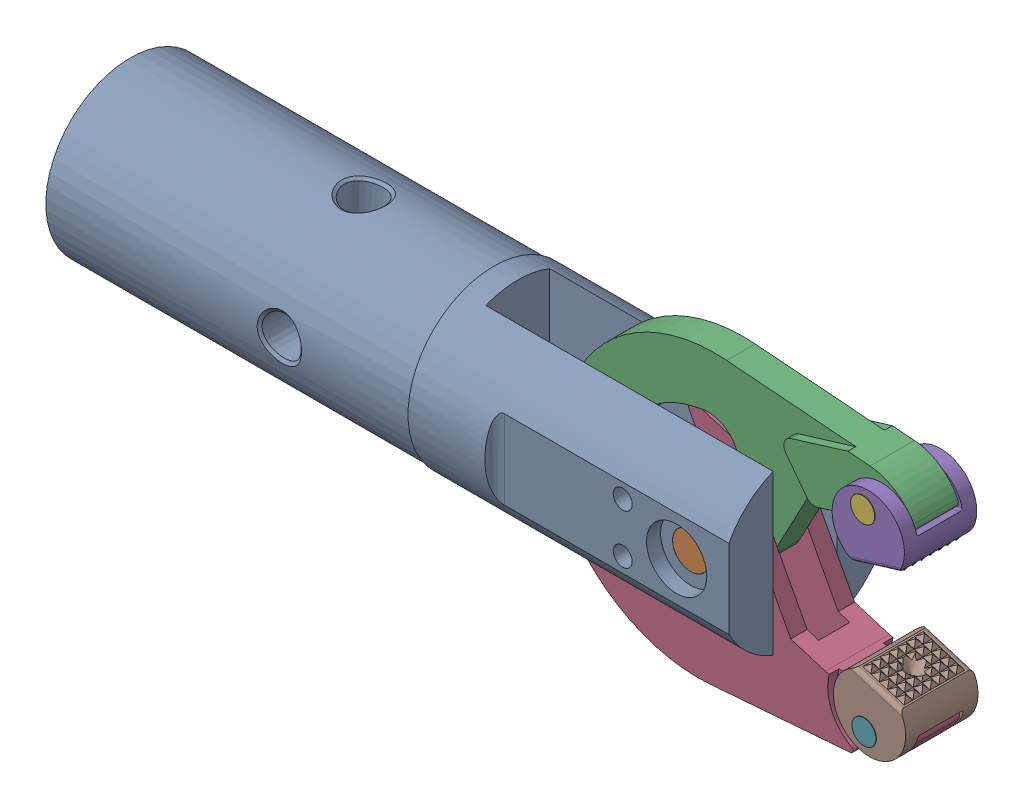
SolidWorks assembly Assem3, configuration Default. Lengths in mm.
Overall size (217.52 103.89 45.21).
8 component instances, 6 part files, 18 mates.
Components (placement in the parent):
- Body-1: Body [Default] at origin size (177.75 45.21 45.21)
- Large_Pin-1: Large_Pin [Default] at (-13.7795 0 -0.1524) x (-0.791073 -0.611722 0) z (0 0 1) size (9.53 9.53 32.77)
- Arm1-1: Arm1 [Default] at (-13.7795 0 0.3302) x (-0.956305 -0.292372 0) z (0 0 -1) size (103 45.53 11.68)
- Arm2-1: Arm2 [Default] at (-13.7795 0 0) x (-0.956305 0.292372 0) z (0 0 1) size (103 45.53 16.81)
- Grip-1: Grip [Default] at (26.2999 20.9388 0.1524) x (0 0 -1) z (0.956305 0.292372 0) size (19.05 17.93 19.05)
- Small_Pin-1: Small_Pin [Default] at (24.926 25.4325 0.4064) x (-0.970898 -0.239493 0) z (0 0 1) size (6.35 6.35 19.16)
- Small_Pin-2: Small_Pin [Default] at (24.926 -25.4325 0.0762) size (6.35 6.35 19.16)
- Grip-2: Grip [Default] at (26.2999 -20.9388 -0.1778) x (0 0 -1) z (-0.956305 0.292372 0) size (19.05 17.93 19.05)
Mates (geometry in assembly coordinates):
- Concentric1: concentric anti-aligned: cylinder of Body-1 through (-13.7795 0 -22.606) axis (0 0 1) radius 4.7892; cylinder of Large_Pin-1 through (-13.7795 0 18.6436) axis (0 0 -1) radius 4.7625
- Concentric2: concentric aligned: cylinder of Large_Pin-1 through (-13.7795 0 18.6436) axis (0 0 -1) radius 4.7625; cylinder of Arm1-1 through (-13.7795 0 6.1722) axis (0 0 -1) radius 4.7688
- Concentric3: concentric anti-aligned: cylinder of Large_Pin-1 through (-13.7795 0 18.6436) axis (0 0 -1) radius 4.7625; cylinder of Arm2-1 through (-13.7795 0 -8.4074) axis (0 0 1) radius 4.7688
- Coincident1: coincident aligned: plane of Body-1 through (-13.7795 0 16.3576) normal (0 0 1); plane of Large_Pin-1 through (-13.7795 0 16.3576) normal (0 0 1)
- Concentric4: concentric anti-aligned: cylinder of Arm1-1 through (18.5039 33.207 6.1722) axis (0 0 -1) radius 3.1813; cylinder of Small_Pin-1 through (18.5039 33.207 -12.0586) axis (0 0 1) radius 3.175
- Concentric5: concentric anti-aligned: cylinder of Grip-1 through (18.5039 33.207 9.6774) axis (0 0 -1) radius 3.1877; cylinder of Small_Pin-1 through (18.5039 33.207 -12.0586) axis (0 0 1) radius 3.175
- Concentric6: concentric aligned: cylinder of Arm2-1 through (29.5131 -16.4522 -8.4074) axis (0 0 1) radius 3.1813; cylinder of Small_Pin-2 through (29.5131 -16.4522 -12.3888) axis (0 0 1) radius 3.175
- Concentric7: concentric anti-aligned: cylinder of Small_Pin-2 through (29.5131 -16.4522 -12.3888) axis (0 0 1) radius 3.175; cylinder of Grip-2 through (29.5131 -16.4522 9.3472) axis (0 0 -1) radius 3.1877
- Coincident2: coincident aligned: plane of Grip-1 through (20.8178 29.1172 -9.3726) normal (0 0 -1); plane of Small_Pin-1 through (18.5039 33.207 -9.3726) normal (0 0 -1)
- Coincident3: coincident aligned: plane of Small_Pin-2 through (29.5131 -16.4522 -9.7028) normal (0 0 -1); plane of Grip-2 through (29.8818 -11.7677 -9.7028) normal (0 0 -1)
- Coincident4: coincident anti-aligned: plane of Arm1-1 through (11.7571 18.8254 6.1722) normal (0 0 1); plane of Grip-1 through (52.0249 57.7171 6.1722) normal (0 0 -1)
- Coincident5: coincident anti-aligned: plane of Arm2-1 through (17.3205 -6.2694 5.842) normal (0 0 1); plane of Grip-2 through (-11.9828 -18.0273 5.842) normal (0 0 -1)
- Coincident6: coincident anti-aligned: plane of Arm1-1 through (15.9696 66.4432 4.0894) normal (0 0 1); plane of Arm2-1 through (41.2625 -47.6454 4.0894) normal (0 0 -1)
- Coincident7: coincident anti-aligned: plane of Body-1 through (-75.692 -22.606 8.4074) normal (0 0 -1); plane of Arm2-1 through (41.2625 -47.6454 8.4074) normal (0 0 1)
- Parallel1: parallel anti-aligned: plane of Arm1-1 through (12.192 23.8868 4.0894) normal (0.492424 -0.870356 0); plane of Grip-1 through (57.153 48.6532 6.1722) normal (-0.492424 0.870356 0)
- Parallel2: parallel anti-aligned: plane of Arm2-1 through (19.8537 -10.6727 -8.4074) normal (0.078459 0.996917 0); plane of Grip-2 through (-11.1658 -7.6454 5.842) normal (-0.078459 -0.996917 0)
- Angle1: planar angle = 0.593412 rad anti-aligned: line of Grip-2 through (35.0017 -17.0653 9.3472) axis (-0.956305 0.292372 0); line of Grip-1 through (21.2518 12.8615 9.6774) axis (0.956305 0.292372 0)
- Angle2: planar angle = 0.296706 rad aligned: line of Grip-1 through (21.2518 12.8615 9.6774) axis (0.956305 0.292372 0)
